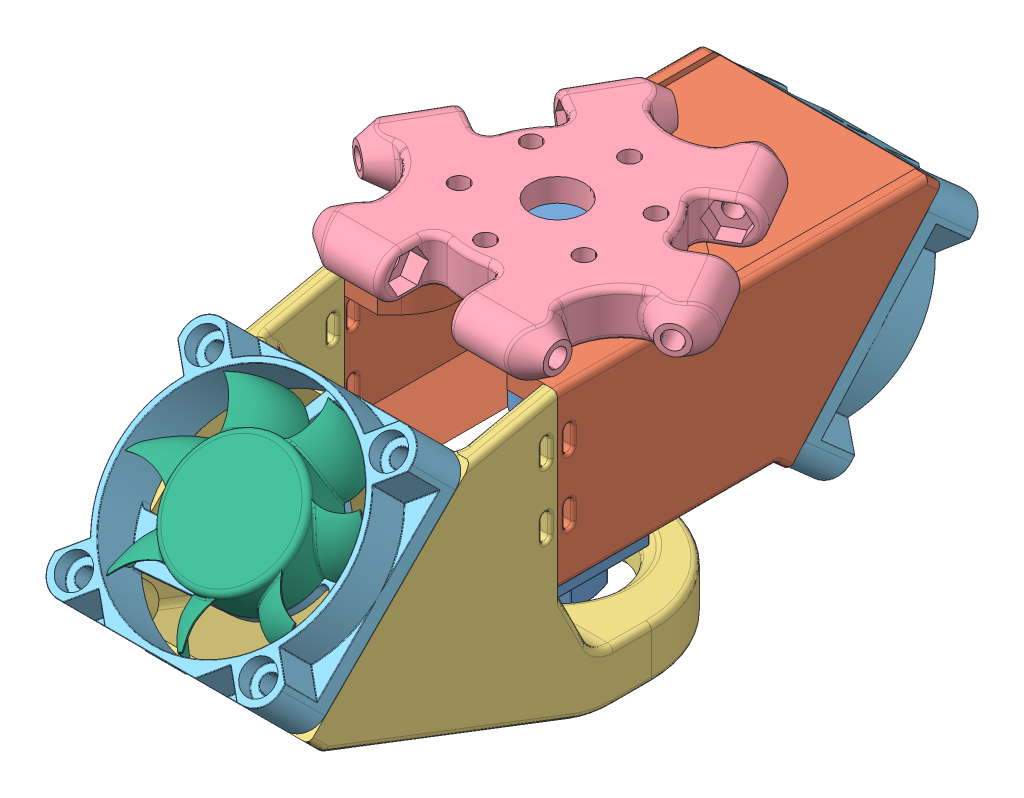
SolidWorks assembly assembled_hotend_groovemount, configuration Default. Lengths in mm.
Overall size (76.36 62.9 125.76).
10 component instances, 6 part files, 17 mates.
Components (placement in the parent):
- mgplus_hotend-1: mgplus_hotend [Default] at origin size (19.55 58.6 19.95)
- Part2^assembled_hotend_groovemount-1: Part2^assembled_hotend_groovemount [Default] x (0 0 -1) z (1 0 0) size (66.76 31.94 40) (virtual)
- Part3^assembled_hotend_groovemount-1: Part3^assembled_hotend_groovemount [Default] x (0 0 -1) z (1 0 0) size (79.41 52.05 40) (virtual)
- effector-1: effector [Groovemount] x (0.866025 0 0.5) z (-0.5 0 0.866025) size (53.68 8.59 59.75)
- 40mm-fan-1: 40mm-fan [По умолчанию] at (-0.9289 -18.7582 -40.3919) x (1 0 0) z (0 -0.662853 -0.74875) size (40.01 40.11 10.82)
  - body^40mm-fan-1: body^40mm-fan [По умолчанию] at (0.9289 7.0036 0) size (40.01 40.11 10.81) (virtual)
  - blades^40mm-fan-1: blades^40mm-fan [По умолчанию] at (0.9289 7.0036 -1) size (37.4 37 9.12) (virtual)
- 40mm-fan-2: 40mm-fan [По умолчанию] at (-0.9289 -25.1947 56.0442) x (1 0 0) z (0 0.707107 0.707107) size (40.01 40.11 10.82)
  - body^40mm-fan-1: body^40mm-fan [По умолчанию] at (0.9289 7.0036 0) size (40.01 40.11 10.81) (virtual)
  - blades^40mm-fan-1: blades^40mm-fan [По умолчанию] at (0.9289 7.0036 -1) size (37.4 37 9.12) (virtual)
Mates (geometry in assembly coordinates):
- InPlace1: in place: plane of ? through (0 0 0) normal (1 0 0); moOrthogonalPlaneRef_w of ? through (-55 0 0) axis (0 0 1); plane of ? through (0 0 0) normal (0 0 -1); unknown of ?
- Coincident1: coincident aligned: plane of Part2^assembled_hotend_groovemount-1; plane of assembly
- Coincident2: coincident aligned: line of ? through (-22 0 0) axis (0 0 1)
- Coincident3: coincident anti-aligned: plane of ? through (0 0 0) normal (0 0 -1)
- InPlace2: in place: plane of ? through (0 0 0) normal (1 0 0); line of ? through (-55 0 0) axis (0 0 1); plane of ? through (0 0 0) normal (0 0 -1); unknown of ?
- Coincident4: coincident aligned: plane of Part3^assembled_hotend_groovemount-1; plane of assembly
- Coincident5: coincident aligned: line of ? through (-22 0 0) axis (0 0 1)
- Coincident6: coincident anti-aligned: plane of ? through (0 0 0) normal (0 0 -1)
- Coincident1: coincident anti-aligned: plane of mgplus_hotend-1 through (0 0 0) normal (0 1 0); plane of effector-1 through (0 0 0) normal (0 -1 0)
- Concentric1: concentric anti-aligned: cylinder of mgplus_hotend-1 through (0 0 0) axis (0 1 0) radius 7.95; cylinder of effector-1 through (0 4.2954 0) axis (0 -1 0) radius 4.625
- Coincident2: coincident aligned: circle of Part2^assembled_hotend_groovemount-1; cylinder of effector-1 through (-10.8253 -4 6.25) axis (0 1 0) radius 1.6
- Coincident3: coincident anti-aligned: plane of Part2^assembled_hotend_groovemount-1 through (16 -10.0336 -44.1089) normal (0 -0.662853 -0.74875); plane of 40mm-fan-1/body^40mm-fan-1 through (-11.4487 -7.8288 -46.0608) normal (0 0.662853 0.74875)
- Concentric2: concentric aligned: cylinder of Part2^assembled_hotend_groovemount-1 through (-16 -10.0336 -44.1089) axis (0 0.662853 0.74875) radius 1.5; cylinder of 40mm-fan-1/body^40mm-fan-1 through (-16 -15.2701 -50.0241) axis (0 0.662853 0.74875) radius 1.5
- Concentric3: concentric aligned: cylinder of Part2^assembled_hotend_groovemount-1 through (16 -10.0336 -44.1089) axis (0 0.662853 0.74875) radius 1.5; cylinder of 40mm-fan-1/body^40mm-fan-1 through (16 -15.2701 -50.0241) axis (0 0.662853 0.74875) radius 1.5
- Coincident4: coincident anti-aligned: plane of Part3^assembled_hotend_groovemount-1 through (0 13.3034 13.3034) normal (0 0.707107 0.707107); plane of 40mm-fan-2/body^40mm-fan-1 through (-11.4487 -35.7596 62.3664) normal (0 -0.707107 -0.707107)
- Concentric4: concentric aligned: cylinder of Part3^assembled_hotend_groovemount-1 through (16 -11.05 37.6569) axis (0 -0.707107 -0.707107) radius 1.5; cylinder of 40mm-fan-2/body^40mm-fan-1 through (16 -5.4639 43.243) axis (0 -0.707107 -0.707107) radius 1.5
- Concentric5: concentric aligned: cylinder of Part3^assembled_hotend_groovemount-1 through (-16 -11.05 37.6569) axis (0 -0.707107 -0.707107) radius 1.5; cylinder of 40mm-fan-2/body^40mm-fan-1 through (-16 -5.4639 43.243) axis (0 -0.707107 -0.707107) radius 1.5
